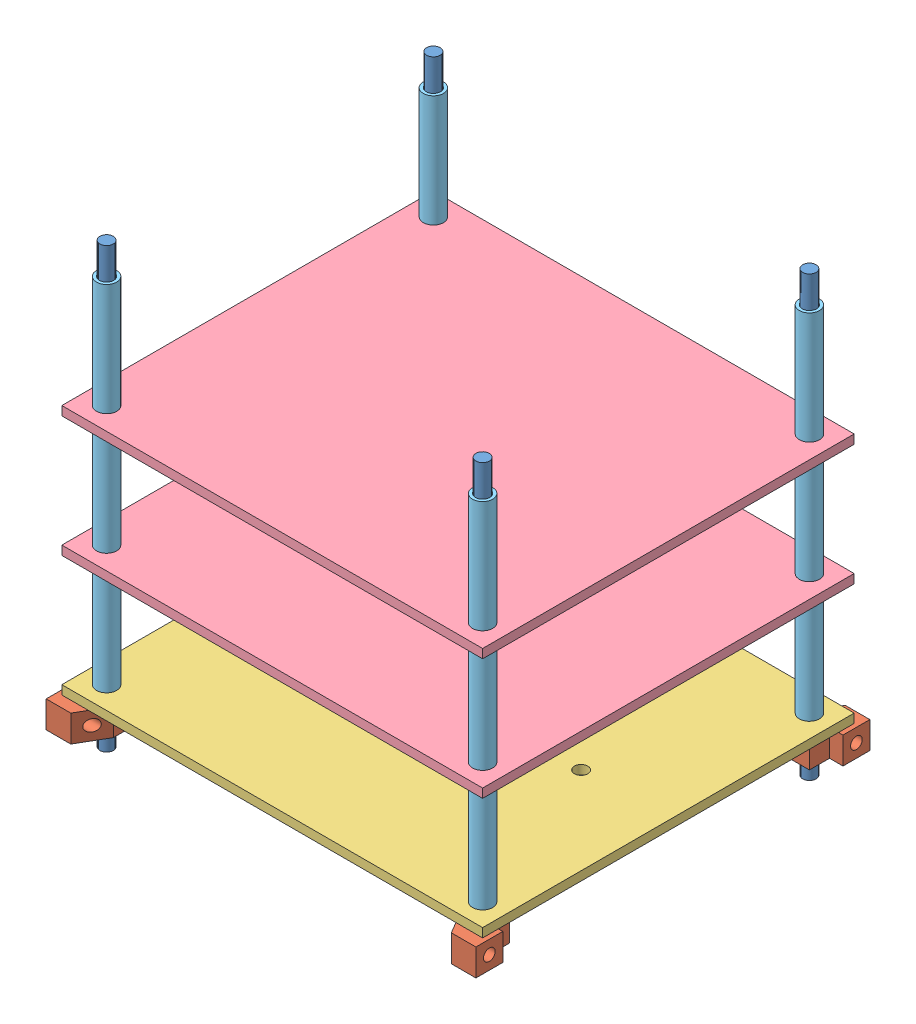
SolidWorks assembly PCB_Stack_3, configuration Default. Lengths in mm.
Overall size (96 98 88).
23 component instances, 5 part files, 52 mates.
Components (placement in the parent):
- PCB_Rod_2-1: PCB_Rod_2 [Default] at origin size (3 98 3)
- PCB_Rod_2-2: PCB_Rod_2 [Default] at (-84 0 0.0003) x (-0.139284 0 0.990253) z (-0.990253 0 -0.139284) size (3 98 3)
- PCB_Rod_2-3: PCB_Rod_2 [Default] at (-83.9998 0 73.0003) x (0.037489 0 0.999297) z (-0.999297 0 0.037489) size (3 98 3)
- PCB_Rod_2-4: PCB_Rod_2 [Default] at (0.0002 0 73) x (0.981991 0 -0.188925) z (0.188925 0 0.981991) size (3 98 3)
- Mounting_Standoff-1: Mounting_Standoff [Default] at (-41.9999 10 36.5001) x (1 0 -0.000003) z (0 -1 0) size (9 10.5 6)
- PCB_Battery-1: PCB_Battery [Default] at (-41.9999 10 36.5001) x (-1 0 0.000003) z (-0.000003 0 -1) size (94 2 83)
- PCB-1: PCB [Default] at (-41.9999 64 36.5001) x (1 0 -0.000003) z (0.000003 0 1) size (94 2 83)
- PCB-2: PCB [Default] at (-41.9999 37 36.5001) x (1 0 -0.000003) z (0.000003 0 1) size (94 2 83)
- Mounting_Standoff-2: Mounting_Standoff [Default] at (-41.9999 4 36.5001) x (-1 0 0.000003) z (0 1 0) size (9 10.5 6)
- Mounting_Standoff-3: Mounting_Standoff [Default] at (-41.9999 4 36.5001) x (1 0 -0.000003) z (0 1 0) size (9 10.5 6)
- Mounting_Standoff-4: Mounting_Standoff [Default] at (-41.9999 10 36.5001) x (-1 0 0.000003) z (0 -1 0) size (9 10.5 6)
- Aluminum Unthreaded Spacer_Battery-1: Aluminum Unthreaded Spacer_Battery [94669A105] at (0 24.5 0) x (0.317635 0 -0.948213) z (0 1 0) size (4.5 4.5 25)
- Aluminum Unthreaded Spacer_Battery-2: Aluminum Unthreaded Spacer_Battery [94669A105] at (0 51.5 0) x (0.317635 0 -0.948213) z (0 1 0) size (4.5 4.5 25)
- Aluminum Unthreaded Spacer_Battery-3: Aluminum Unthreaded Spacer_Battery [94669A105] at (0 78.5 0) x (-0.841831 0 -0.539741) z (0 1 0) size (4.5 4.5 25)
- Aluminum Unthreaded Spacer_Battery-4: Aluminum Unthreaded Spacer_Battery [94669A105] at (0.0002 24.5 73) x (0.317635 0 -0.948213) z (0 1 0) size (4.5 4.5 25)
- Aluminum Unthreaded Spacer_Battery-5: Aluminum Unthreaded Spacer_Battery [94669A105] at (0.0002 51.5 73) x (0.317635 0 -0.948213) z (0 1 0) size (4.5 4.5 25)
- Aluminum Unthreaded Spacer_Battery-6: Aluminum Unthreaded Spacer_Battery [94669A105] at (0.0002 78.5 73) x (-0.286549 0 -0.958066) z (0 1 0) size (4.5 4.5 25)
- Aluminum Unthreaded Spacer_Battery-7: Aluminum Unthreaded Spacer_Battery [94669A105] at (-83.9998 24.5 73.0003) x (0.317635 0 -0.948213) z (0 1 0) size (4.5 4.5 25)
- Aluminum Unthreaded Spacer_Battery-8: Aluminum Unthreaded Spacer_Battery [94669A105] at (-83.9998 51.5 73.0003) x (0.317635 0 -0.948213) z (0 1 0) size (4.5 4.5 25)
- Aluminum Unthreaded Spacer_Battery-9: Aluminum Unthreaded Spacer_Battery [94669A105] at (-83.9998 78.5 73.0003) x (-0.883236 0 -0.468929) z (0 1 0) size (4.5 4.5 25)
- Aluminum Unthreaded Spacer_Battery-10: Aluminum Unthreaded Spacer_Battery [94669A105] at (-84 51.5 0.0003) x (0.317635 0 -0.948213) z (0 1 0) size (4.5 4.5 25)
- Aluminum Unthreaded Spacer_Battery-11: Aluminum Unthreaded Spacer_Battery [94669A105] at (-84 78.5 0.0003) x (-0.872408 0 -0.488777) z (0 1 0) size (4.5 4.5 25)
- Aluminum Unthreaded Spacer_Battery-12: Aluminum Unthreaded Spacer_Battery [94669A105] at (-84 24.5 0.0003) x (0.317635 0 -0.948213) z (0 1 0) size (4.5 4.5 25)
Mates (geometry in assembly coordinates):
- Concentric1: concentric aligned: cylinder of PCB_Rod_2-1 through (0 98 0) axis (0 -1 0) radius 1.5; cylinder of PCB_Battery-1 through (0 12 0) axis (0 -1 0) radius 1.5
- Concentric2: concentric aligned: cylinder of PCB_Rod_2-4 through (0.0002 98 73) axis (0 -1 0) radius 1.5; cylinder of PCB_Battery-1 through (0.0002 12 73) axis (0 -1 0) radius 1.5
- Concentric3: concentric aligned: cylinder of PCB_Rod_2-3 through (-83.9998 98 73.0003) axis (0 -1 0) radius 1.5; cylinder of PCB_Battery-1 through (-83.9998 12 73.0003) axis (0 -1 0) radius 1.5
- Concentric4: concentric aligned: cylinder of PCB_Rod_2-2 through (-84 98 0.0003) axis (0 -1 0) radius 1.5; cylinder of PCB_Battery-1 through (-84 12 0.0003) axis (0 -1 0) radius 1.5
- Concentric10: concentric aligned: cylinder of PCB_Rod_2-2 through (-84 98 0.0003) axis (0 -1 0) radius 1.5; cylinder of PCB-2 through (-84 39 0.0003) axis (0 -1 0) radius 1.5
- Concentric11: concentric aligned: cylinder of PCB_Rod_2-3 through (-83.9998 98 73.0003) axis (0 -1 0) radius 1.5; cylinder of PCB-2 through (-83.9998 39 73.0003) axis (0 -1 0) radius 1.5
- Concentric12: concentric aligned: cylinder of PCB_Rod_2-1 through (0 98 0) axis (0 -1 0) radius 1.5; cylinder of PCB-2 through (0 39 0) axis (0 -1 0) radius 1.5
- Concentric13: concentric aligned: cylinder of PCB_Rod_2-4 through (0.0002 98 73) axis (0 -1 0) radius 1.5; cylinder of PCB-2 through (0.0002 39 73) axis (0 -1 0) radius 1.5
- Distance1: distance = 25 mm anti-aligned: plane of PCB-2 through (-41.9999 37 36.5001) normal (0 -1 0); plane of PCB_Battery-1 through (-41.9999 12 36.5001) normal (0 1 0)
- Concentric14: concentric aligned: cylinder of PCB_Rod_2-4 through (0.0002 98 73) axis (0 -1 0) radius 1.5; cylinder of PCB-1 through (0.0002 66 73) axis (0 -1 0) radius 1.5
- Concentric15: concentric aligned: cylinder of PCB_Rod_2-1 through (0 98 0) axis (0 -1 0) radius 1.5; cylinder of PCB-1 through (0 66 0) axis (0 -1 0) radius 1.5
- Distance2: distance = 25 mm anti-aligned: plane of PCB-1 through (-41.9999 64 36.5001) normal (0 -1 0); plane of PCB-2 through (-41.9999 39 36.5001) normal (0 1 0)
- Concentric16: concentric anti-aligned: cylinder of PCB_Rod_2-1 through (0 98 0) axis (0 -1 0) radius 1.5; cylinder of Mounting_Standoff-1 through (0 4 0) axis (0 1 0) radius 1.55
- Coincident1: coincident anti-aligned: plane of Mounting_Standoff-1 through (-41.9999 10 36.5001) normal (0 1 0); plane of PCB_Battery-1 through (-41.9999 10 36.5001) normal (0 -1 0)
- Parallel1: parallel aligned: plane of Mounting_Standoff-1 through (6 4 -7.5) normal (1 0 -0.000003); plane of PCB_Battery-1 through (5 12 -5) normal (1 0 -0.000003)
- Concentric17: concentric aligned: cylinder of PCB_Rod_2-2 through (-84 98 0.0003) axis (0 -1 0) radius 1.5; cylinder of Mounting_Standoff-2 through (-84 10 0.0003) axis (0 -1 0) radius 1.55
- Parallel3: parallel aligned: plane of PCB_Battery-1 through (-89 12 -4.9997) normal (-1 0 0.000003); plane of Mounting_Standoff-2 through (-90 10 -7.4997) normal (-1 0 0.000003)
- Coincident2: coincident anti-aligned: plane of PCB_Battery-1 through (-41.9999 10 36.5001) normal (0 -1 0); plane of Mounting_Standoff-2 through (-41.9999 10 36.5001) normal (0 1 0)
- Concentric18: concentric aligned: cylinder of PCB_Rod_2-4 through (0.0002 98 73) axis (0 -1 0) radius 1.5; cylinder of Mounting_Standoff-3 through (0.0002 10 73) axis (0 -1 0) radius 1.55
- Coincident3: coincident anti-aligned: plane of PCB_Battery-1 through (-41.9999 10 36.5001) normal (0 -1 0); plane of Mounting_Standoff-3 through (-41.9999 10 36.5001) normal (0 1 0)
- Parallel4: parallel aligned: plane of PCB_Battery-1 through (5.0003 12 78) normal (0.000003 0 1); plane of Mounting_Standoff-3 through (0.5003 10 80.5) normal (0.000003 0 1)
- Concentric19: concentric anti-aligned: cylinder of PCB_Rod_2-3 through (-83.9998 98 73.0003) axis (0 -1 0) radius 1.5; cylinder of Mounting_Standoff-4 through (-83.9998 4 73.0003) axis (0 1 0) radius 1.55
- Coincident5: coincident anti-aligned: plane of PCB_Battery-1 through (-41.9999 10 36.5001) normal (0 -1 0); plane of Mounting_Standoff-4 through (-41.9999 10 36.5001) normal (0 1 0)
- Parallel5: parallel aligned: plane of PCB_Battery-1 through (5.0003 12 78) normal (0.000003 0 1); plane of Mounting_Standoff-4 through (-84.4997 4 80.5003) normal (0.000003 0 1)
- Distance3: distance = 10 mm aligned: plane of PCB_Battery-1 through (-41.9999 10 36.5001) normal (0 -1 0); plane of PCB_Rod_2-1 through (0 0 0) normal (0 -1 0)
- Coincident6: coincident aligned: plane of PCB_Rod_2-1 through (0 0 0) normal (0 -1 0); plane of PCB_Rod_2-4 through (0.0002 0 73) normal (0 -1 0)
- Coincident7: coincident aligned: plane of PCB_Rod_2-1 through (0 0 0) normal (0 -1 0); plane of PCB_Rod_2-2 through (-84 0 0.0003) normal (0 -1 0)
- Coincident8: coincident aligned: plane of PCB_Rod_2-1 through (0 0 0) normal (0 -1 0); plane of PCB_Rod_2-3 through (-83.9998 0 73.0003) normal (0 -1 0)
- Concentric20: concentric aligned: cylinder of PCB_Rod_2-1 through (0 98 0) axis (0 -1 0) radius 1.5; cylinder of Aluminum Unthreaded Spacer_Battery-1 through (0 37 0) axis (0 -1 0) radius 1.6
- Coincident9: coincident anti-aligned: plane of PCB-2 through (-41.9999 37 36.5001) normal (0 -1 0); plane of Aluminum Unthreaded Spacer_Battery-1 through (0 37 0) normal (0 1 0)
- Concentric21: concentric aligned: cylinder of PCB_Rod_2-1 through (0 98 0) axis (0 -1 0) radius 1.5; cylinder of Aluminum Unthreaded Spacer_Battery-2 through (0 64 0) axis (0 -1 0) radius 1.6
- Coincident10: coincident anti-aligned: plane of PCB-1 through (-41.9999 64 36.5001) normal (0 -1 0); plane of Aluminum Unthreaded Spacer_Battery-2 through (0 64 0) normal (0 1 0)
- Concentric22: concentric aligned: cylinder of PCB_Rod_2-1 through (0 98 0) axis (0 -1 0) radius 1.5; cylinder of Aluminum Unthreaded Spacer_Battery-3 through (0 91 0) axis (0 -1 0) radius 1.6
- Coincident11: coincident anti-aligned: plane of PCB-1 through (-41.9999 66 36.5001) normal (0 1 0); plane of Aluminum Unthreaded Spacer_Battery-3 through (0 66 0) normal (0 -1 0)
- Concentric23: concentric aligned: cylinder of PCB_Rod_2-4 through (0.0002 98 73) axis (0 -1 0) radius 1.5; cylinder of Aluminum Unthreaded Spacer_Battery-4 through (0.0002 37 73) axis (0 -1 0) radius 1.6
- Coincident12: coincident anti-aligned: plane of PCB-2 through (-41.9999 37 36.5001) normal (0 -1 0); plane of Aluminum Unthreaded Spacer_Battery-4 through (0.0002 37 73) normal (0 1 0)
- Concentric24: concentric aligned: cylinder of PCB_Rod_2-4 through (0.0002 98 73) axis (0 -1 0) radius 1.5; cylinder of Aluminum Unthreaded Spacer_Battery-5 through (0.0002 64 73) axis (0 -1 0) radius 1.6
- Coincident13: coincident anti-aligned: plane of PCB-1 through (-41.9999 64 36.5001) normal (0 -1 0); plane of Aluminum Unthreaded Spacer_Battery-5 through (0.0002 64 73) normal (0 1 0)
- Concentric25: concentric aligned: cylinder of PCB_Rod_2-4 through (0.0002 98 73) axis (0 -1 0) radius 1.5; cylinder of Aluminum Unthreaded Spacer_Battery-6 through (0.0002 91 73) axis (0 -1 0) radius 1.6
- Coincident14: coincident anti-aligned: plane of PCB-1 through (-41.9999 66 36.5001) normal (0 1 0); plane of Aluminum Unthreaded Spacer_Battery-6 through (0.0002 66 73) normal (0 -1 0)
- Concentric26: concentric aligned: cylinder of PCB_Rod_2-3 through (-83.9998 98 73.0003) axis (0 -1 0) radius 1.5; cylinder of Aluminum Unthreaded Spacer_Battery-7 through (-83.9998 37 73.0003) axis (0 -1 0) radius 1.6
- Coincident15: coincident anti-aligned: plane of PCB-2 through (-41.9999 37 36.5001) normal (0 -1 0); plane of Aluminum Unthreaded Spacer_Battery-7 through (-83.9998 37 73.0003) normal (0 1 0)
- Concentric27: concentric aligned: cylinder of PCB_Rod_2-3 through (-83.9998 98 73.0003) axis (0 -1 0) radius 1.5; cylinder of Aluminum Unthreaded Spacer_Battery-8 through (-83.9998 64 73.0003) axis (0 -1 0) radius 1.6
- Coincident16: coincident anti-aligned: plane of PCB-1 through (-41.9999 64 36.5001) normal (0 -1 0); plane of Aluminum Unthreaded Spacer_Battery-8 through (-83.9998 64 73.0003) normal (0 1 0)
- Concentric28: concentric aligned: cylinder of PCB_Rod_2-3 through (-83.9998 98 73.0003) axis (0 -1 0) radius 1.5; cylinder of Aluminum Unthreaded Spacer_Battery-9 through (-83.9998 91 73.0003) axis (0 -1 0) radius 1.6
- Coincident17: coincident anti-aligned: plane of PCB-1 through (-41.9999 66 36.5001) normal (0 1 0); plane of Aluminum Unthreaded Spacer_Battery-9 through (-83.9998 66 73.0003) normal (0 -1 0)
- Concentric29: concentric aligned: cylinder of PCB_Rod_2-2 through (-84 98 0.0003) axis (0 -1 0) radius 1.5; cylinder of Aluminum Unthreaded Spacer_Battery-12 through (-84 37 0.0003) axis (0 -1 0) radius 1.6
- Coincident18: coincident anti-aligned: plane of PCB-2 through (-41.9999 37 36.5001) normal (0 -1 0); plane of Aluminum Unthreaded Spacer_Battery-12 through (-84 37 0.0003) normal (0 1 0)
- Concentric30: concentric aligned: cylinder of PCB_Rod_2-2 through (-84 98 0.0003) axis (0 -1 0) radius 1.5; cylinder of Aluminum Unthreaded Spacer_Battery-10 through (-84 64 0.0003) axis (0 -1 0) radius 1.6
- Coincident19: coincident anti-aligned: plane of PCB-1 through (-41.9999 64 36.5001) normal (0 -1 0); plane of Aluminum Unthreaded Spacer_Battery-10 through (-84 64 0.0003) normal (0 1 0)
- Concentric31: concentric aligned: cylinder of PCB_Rod_2-2 through (-84 98 0.0003) axis (0 -1 0) radius 1.5; cylinder of Aluminum Unthreaded Spacer_Battery-11 through (-84 96.6611 0.0003) axis (0 -1 0) radius 1.6
- Coincident20: coincident anti-aligned: plane of PCB-1 through (-41.9999 66 36.5001) normal (0 1 0); plane of Aluminum Unthreaded Spacer_Battery-11 through (-84 71.6611 0.0003) normal (0 -1 0)
